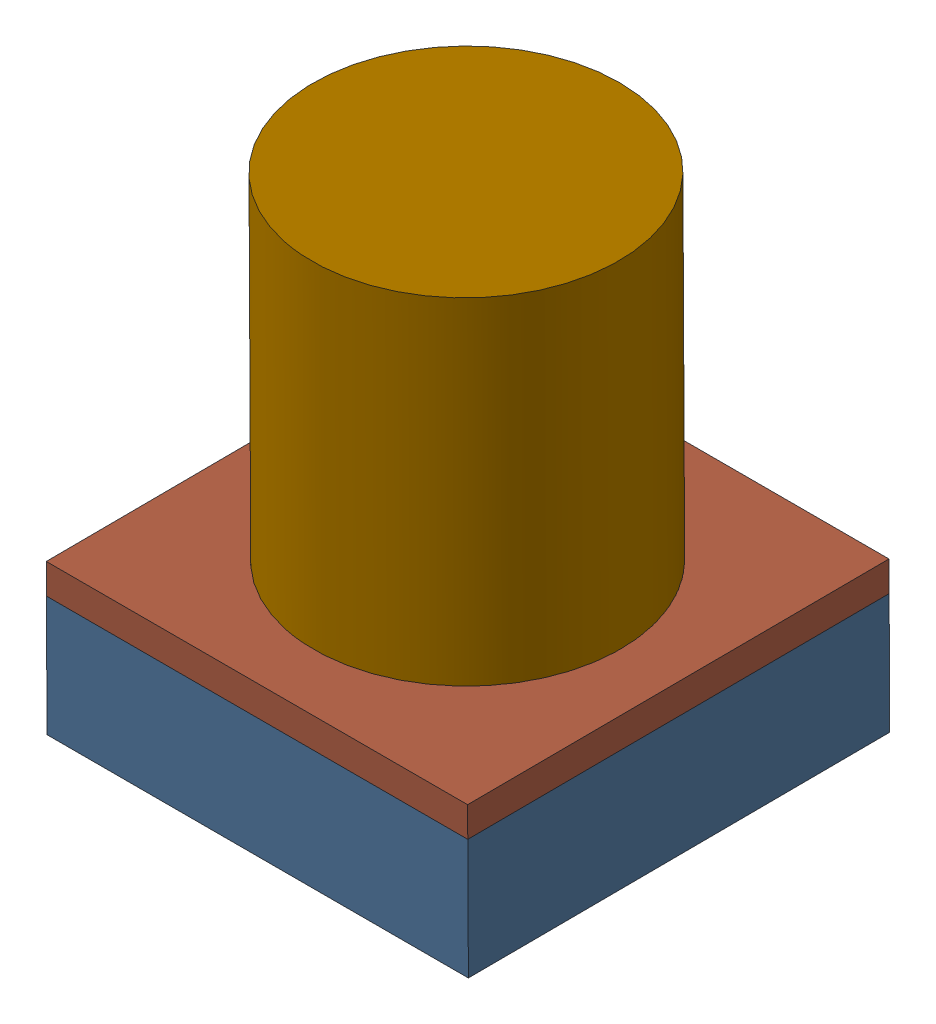
SolidWorks assembly Final, configuration Default. Lengths in mm.
Overall size (70 81.33 70.14).
20 component instances, 12 part files, 30 mates.
Components (placement in the parent):
- MACOR-1: MACOR [Default] at (-35 62.6262 110.6099) x (0.813179 0.002983 -0.582006) z (0.582013 -0.004168 0.813169) size (10 16 10)
- Rod-1: Rod [Default] at (-35 35.3478 110.4701) x (-0.020933 -0.005124 0.999768) z (-0.999781 0.000107 -0.020933) size (3 40 3)
- Bearing-5: Bearing [Default] at (-33.8795 64.8828 108.6129) x (0 -0.999987 -0.005125) z (-0.999781 0.000107 -0.020933) size (1.6 1.6 1.6)
- Bearing-6: Bearing [Default] at (-37.2662 64.9145 110.229) x (0 -0.999987 -0.005125) z (-0.999781 0.000107 -0.020933) size (1.6 1.6 1.6)
- Bearing-7: Bearing [Default] at (-33.9141 58.2749 108.56) x (0 -0.999987 -0.005125) z (-0.999781 0.000107 -0.020933) size (1.6 1.6 1.6)
- Bearing-8: Bearing [Default] at (-37.2061 58.0134 109.9357) x (0 -0.999987 -0.005125) z (-0.999781 0.000107 -0.020933) size (1.6 1.6 1.6)
- Cover2-2: Cover2 [Default] at (-35 67.4339 110.6345) x (-0.019742 -0.005124 0.999792) z (0.999805 -0.000101 0.019742) size (20 1 20)
- PZT-1: PZT [Default] at (-35 64.4983 110.6195) x (0 -0.999987 -0.005125) z (-0.814984 -0.00297 0.579476) size (15 10 10)
- 套筒-1: 套筒 [默认] at (-35 26.4344 110.4244) x (-1 0 0) z (0 0.005125 -0.999987) size (20 40 20)
- 底座1-1: 底座1 [默认] at (-35 27.4344 110.4295) x (0 0.005125 -0.999987) z (-1 0 0) size (45 5 45)
- 91290A010_BLACK-OXIDE CLASS 12.9 SOCKET HEAD CAP SCREW-1: 91290A010_BLACK-OXIDE CLASS 12.9 SOCKET HEAD CAP SCREW [91290A010] at (-34.8421 64.4749 102.6208) x (0.999998 0.00001 -0.00203) z (0 -0.999987 -0.005125) size (3.8 3.8 5.09)
- 91290A010_BLACK-OXIDE CLASS 12.9 SOCKET HEAD CAP SCREW-2: 91290A010_BLACK-OXIDE CLASS 12.9 SOCKET HEAD CAP SCREW [91290A010] at (-27.0016 64.4331 110.7771) x (0.999998 0.00001 -0.00203) z (0 -0.999987 -0.005125) size (3.8 3.8 5.09)
- 91290A010_BLACK-OXIDE CLASS 12.9 SOCKET HEAD CAP SCREW-3: 91290A010_BLACK-OXIDE CLASS 12.9 SOCKET HEAD CAP SCREW [91290A010] at (-42.9984 64.4347 110.4612) x (0.999998 0.00001 -0.00203) z (0 -0.999987 -0.005125) size (3.8 3.8 5.09)
- 91290A010_BLACK-OXIDE CLASS 12.9 SOCKET HEAD CAP SCREW-4: 91290A010_BLACK-OXIDE CLASS 12.9 SOCKET HEAD CAP SCREW [91290A010] at (-35.1579 64.3929 118.6175) x (0.999998 0.00001 -0.00203) z (0 -0.999987 -0.005125) size (3.8 3.8 5.09)
- Outer-3: Outer [Default] at (-35.0387 22.4352 110.2651) x (0.990335 -0.000711 0.138693) z (-0.138695 -0.005076 0.990322) size (51 58 51)
- OpAmp-1: OpAmp [Default] at (-113.7592 40.5679 112.1504) x (0 -0.005125 0.999987) z (1 0 0) size (70 28.12 70)
  - Part2-1: Part2 [Default] at (-1.7924 21.1422 78.7206) size (70 20 70)
  - Part1-1: Part1 [Default] at (-1.7924 16.1422 78.7206) size (70 5 70)
  - 91290A138_BLACK-OXIDE CLASS 12.9 SOCKET HEAD CAP SCREW-1: 91290A138_BLACK-OXIDE CLASS 12.9 SOCKET HEAD CAP SCREW [91290A138] at (-20.2924 13.1422 78.7206) x (-0.33762 0 -0.941282) z (0 -1 0) size (7 7 9.29)
  - 91290A138_BLACK-OXIDE CLASS 12.9 SOCKET HEAD CAP SCREW-2: 91290A138_BLACK-OXIDE CLASS 12.9 SOCKET HEAD CAP SCREW [91290A138] at (16.7076 13.1422 78.7206) x (-0.33762 0 -0.941282) z (0 -1 0) size (7 7 9.29)
Mates (geometry in assembly coordinates):
- Tangent4: tangent anti-aligned: cylinder of Rod-1 through (-35 75.3473 110.6751) axis (0 -0.999987 -0.005125) radius 1.5; sphere of Bearing-5
- Lock2: lock: unknown of Rod-1; unknown of Bearing-5
- Tangent6: tangent anti-aligned: cylinder of Rod-1 through (-35 75.3473 110.6751) axis (0 -0.999987 -0.005125) radius 1.5; sphere of Bearing-6
- Lock3: lock: unknown of Rod-1; unknown of Bearing-5
- Lock4: lock: unknown of Rod-1; unknown of Bearing-6
- Tangent9: tangent anti-aligned: cylinder of Rod-1 through (-35 75.3473 110.6751) axis (0 -0.999987 -0.005125) radius 1.5; sphere of Bearing-7
- Lock5: lock: unknown of Rod-1; unknown of Bearing-7
- Tangent11: tangent anti-aligned: cylinder of Rod-1 through (-35 75.3473 110.6751) axis (0 -0.999987 -0.005125) radius 1.5; sphere of Bearing-8
- Lock6: lock: unknown of Rod-1; unknown of Bearing-8
- Concentric6: concentric aligned: cylinder of MACOR-1 through (-35 65.4982 110.6246) axis (0 -0.999987 -0.005125) radius 3; cylinder of Rod-1 through (-35 75.3473 110.6751) axis (0 -0.999987 -0.005125) radius 1.5
- Lock7: lock: unknown of MACOR-1; unknown of Rod-1
- Coincident1: coincident aligned: cylinder of MACOR-1 through (-35 65.4982 110.6246) axis (0 0.999987 0.005125) radius 4.4; circle of PZT-1
- Coincident2: coincident aligned: circle of MACOR-1; plane of PZT-1 through (-35 64.4983 110.6195) normal (0 0.999987 0.005125)
- Concentric15: concentric anti-aligned: cylinder of Cover2-2 through (-35 66.4339 110.6294) axis (0 0.999987 0.005125) radius 10; cylinder of 套筒-1 through (-35 66.4339 110.6294) axis (0 -0.999987 -0.005125) radius 10
- Coincident9: coincident anti-aligned: plane of Cover2-2 through (-35 66.4339 110.6294) normal (0 -0.999987 -0.005125); plane of 套筒-1 through (-35 66.4339 110.6294) normal (0 0.999987 0.005125)
- Concentric16: concentric anti-aligned: circle of Rod-1; circle of Cover2-2
- Coincident10: coincident aligned: plane of 套筒-1 through (-35 26.4344 110.4244) normal (0 -0.999987 -0.005125); circle of 底座1-1
- Concentric17: concentric anti-aligned: circle of 套筒-1; circle of 底座1-1
- Lock8: lock: unknown of Rod-1; unknown of 套筒-1
- Coincident15: coincident anti-aligned: line of 套筒-1 through (-27 26.4652 104.4245) axis (-1 0 0); line of 底座1-1 through (-43.3104 26.4652 104.4245) axis (1 0 0)
- Lock9: lock: unknown of 套筒-1; unknown of 底座1-1
- Coincident20: coincident anti-aligned: plane of Cover2-2 through (-35 67.4339 110.6345) normal (0 0.999987 0.005125); plane of 91290A010_BLACK-OXIDE CLASS 12.9 SOCKET HEAD CAP SCREW-1 through (-34.8421 67.4749 102.6362) normal (0 -0.999987 -0.005125)
- Concentric26: concentric anti-aligned: circle of Cover2-2; circle of 91290A010_BLACK-OXIDE CLASS 12.9 SOCKET HEAD CAP SCREW-1
- Coincident21: coincident anti-aligned: plane of Cover2-2 through (-35 67.4339 110.6345) normal (0 0.999987 0.005125); plane of 91290A010_BLACK-OXIDE CLASS 12.9 SOCKET HEAD CAP SCREW-3 through (-42.9984 67.4347 110.4766) normal (0 -0.999987 -0.005125)
- Coincident22: coincident anti-aligned: plane of Cover2-2 through (-35 67.4339 110.6345) normal (0 0.999987 0.005125); circle of 91290A010_BLACK-OXIDE CLASS 12.9 SOCKET HEAD CAP SCREW-4
- Coincident23: coincident anti-aligned: plane of Cover2-2 through (-35 67.4339 110.6345) normal (0 0.999987 0.005125); plane of 91290A010_BLACK-OXIDE CLASS 12.9 SOCKET HEAD CAP SCREW-2 through (-27.0016 67.4331 110.7925) normal (0 -0.999987 -0.005125)
- Concentric27: concentric anti-aligned: circle of Cover2-2; circle of 91290A010_BLACK-OXIDE CLASS 12.9 SOCKET HEAD CAP SCREW-2
- Concentric28: concentric aligned: circle of Cover2-2; circle of 91290A010_BLACK-OXIDE CLASS 12.9 SOCKET HEAD CAP SCREW-3
- Concentric29: concentric anti-aligned: circle of Cover2-2; circle of 91290A010_BLACK-OXIDE CLASS 12.9 SOCKET HEAD CAP SCREW-4
- Concentric30: concentric anti-aligned: cylinder of Outer-3 through (-35.0387 80.4344 110.5623) axis (0 -0.999987 -0.005125) radius 25.5; cylinder of OpAmp-1/Part1-1 through (-35.0387 22.4352 110.2651) axis (0 0.999987 0.005125) radius 25.5
